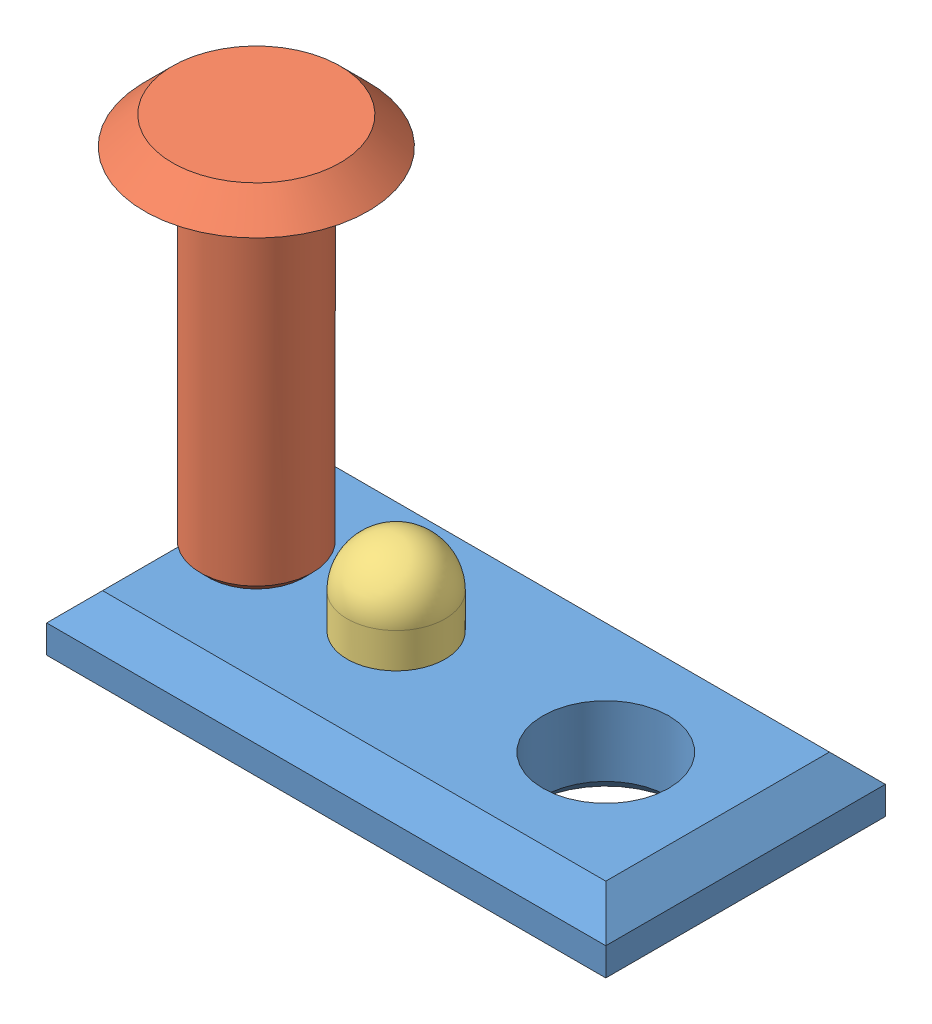
SolidWorks assembly Yucra_Fabrizio_E04, configuration Predeterminado. Lengths in mm.
Overall size (223.05 165 100).
3 component instances, 3 part files, 4 mates.
Components (placement in the parent):
- Yucra_Fabrizio_P56A-1: Yucra_Fabrizio_P56A [Predeterminado] at (-37.2817 -16.8108 200) size (200 30 100)
- Yucra_Fabrizio_P56B-1: Yucra_Fabrizio_P56B [Predeterminado] at (-112.2817 148.1892 200) x (-0.9738 0 -0.227406) z (0 -1 0) size (80 80 160)
- Yucra_Fabrizio_P56C-1: Yucra_Fabrizio_P56C [Predeterminado] at (-62.2817 -6.8108 200) x (0.986743 0 -0.162293) z (0 -1 0) size (35 35 50)
Mates (geometry in assembly coordinates):
- Concéntrica1: concentric: cylinder of Yucra_Fabrizio_P56A-1 through (-112.2817 -16.8118 200) axis (0 1 0) radius 7.5; cylinder of Yucra_Fabrizio_P56B-1 through (-112.2817 148.1892 200) axis (0 1 0) radius 7.5
- Coincidente1: coincident anti-aligned: plane of Yucra_Fabrizio_P56A-1 through (-37.2817 13.1892 200) normal (0 1 0); plane of Yucra_Fabrizio_P56B-1 through (-108.4158 13.1892 183.4454) normal (0 -1 0)
- Concéntrica2: concentric: cylinder of Yucra_Fabrizio_P56A-1 through (-62.2817 -16.8118 200) axis (0 1 0) radius 15; cylinder of Yucra_Fabrizio_P56C-1 through (-62.2817 -6.8108 200) axis (0 -1 0) radius 15
- Coincidente2: coincident anti-aligned: plane of Yucra_Fabrizio_P56A-1 through (-37.2817 13.1892 200) normal (0 1 0); plane of Yucra_Fabrizio_P56C-1 through (-59.8473 13.1892 214.8011) normal (0 -1 0)
